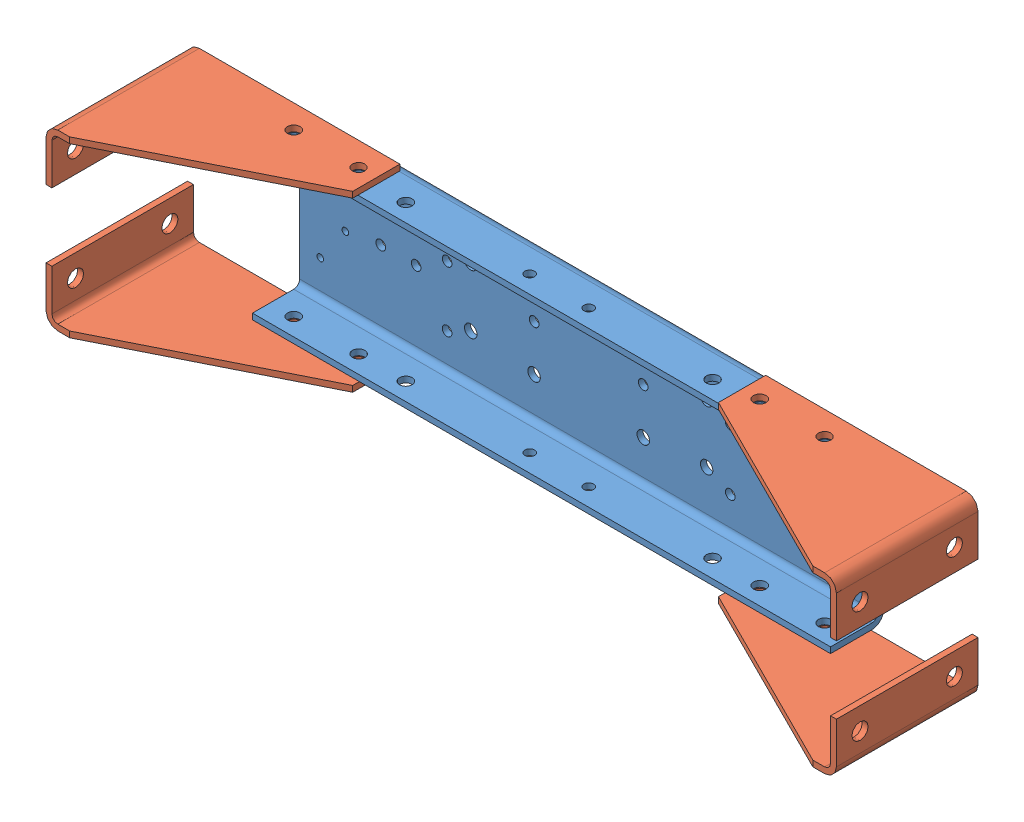
SolidWorks assembly SUB-1700-111, configuration Collapsed - No fasteners. Lengths in mm.
Overall size (850.9 187.32 165.1).
21 component instances, 4 part files, 56 mates.
Components (placement in the parent):
- 2686-CC2-1: 2686-CC2 [Default] at (0 0 -38.1) x (-1 0 0) z (0 0 -1)
- 2688-CC2-1: 2688-CC2 [2688-CC2-001] at (-425.45 -93.6625 0) x (1 0 0) z (0 0 -1)
- 2688-CC2-2: 2688-CC2 [2688-CC2-002] at (-425.45 93.6625 0)
- 2688-CC2-3: 2688-CC2 [2688-CC2-001] at (425.45 93.6625 0) x (-1 0 0) z (0 0 -1)
- 2688-CC2-4: 2688-CC2 [2688-CC2-002] at (425.45 -93.6625 0) x (-1 0 0) z (0 0 1)
- 08130XXXFH8Y-1: 08130XXXFH8Y [08130125FH8Y] at (-215.9 -93.6625 0) x (-0.388505 0 0.921447) z (0 -1 0) (suppressed, hidden)
- 08130XXXFH8Y-9: 08130XXXFH8Y [08130125FH8Y] at (215.9 93.6625 0) x (-0.948085 0 0.318017) z (0 1 0) (suppressed, hidden)
- 08130XXXFH8Y-7: 08130XXXFH8Y [08130125FH8Y] at (215.9 -93.6625 0) x (0.126811 0 0.991927) z (0 -1 0) (suppressed, hidden)
- 08130XXXFH8Y-11: 08130XXXFH8Y [08130125FH8Y] at (-215.9 93.6625 0) x (-0.668287 0 0.743903) z (0 1 0) (suppressed, hidden)
- 08130XXXFH8Y-2: 08130XXXFH8Y [08130125FH8Y] at (-285.75 -93.6625 0) x (0.84446 0 0.535618) z (0 -1 0) (suppressed, hidden)
- 08130XXXFH8Y-12: 08130XXXFH8Y [08130125FH8Y] at (-285.75 93.6625 0) x (-0.913136 0 -0.407655) z (0 1 0) (suppressed, hidden)
- 08130XXXFH8Y-10: 08130XXXFH8Y [08130125FH8Y] at (285.75 93.6625 0) x (-0.594714 0 0.803937) z (0 1 0) (suppressed, hidden)
- 08130XXXFH8Y-8: 08130XXXFH8Y [08130125FH8Y] at (285.75 -93.6625 0) x (0.463299 0 -0.886202) z (0 -1 0) (suppressed, hidden)
- XXXXFLN8Y-2: XXXXFLN8Y [0813FLN8Y] at (-285.75 -80.1688 0) x (0.884733 0 0.466098) z (0 1 0) (suppressed, hidden)
- XXXXFLN8Y-3: XXXXFLN8Y [0813FLN8Y] at (-215.9 80.1688 0) x (-0.573629 0 -0.819115) z (0 -1 0) (suppressed, hidden)
- XXXXFLN8Y-5: XXXXFLN8Y [0813FLN8Y] at (-285.75 80.1688 0) x (0.44022 0 0.89789) z (0 -1 0) (suppressed, hidden)
- XXXXFLN8Y-1: XXXXFLN8Y [0813FLN8Y] at (-215.9 -80.1688 0) x (0.278333 0 0.960485) z (0 1 0) (suppressed, hidden)
- XXXXFLN8Y-6: XXXXFLN8Y [0813FLN8Y] at (215.9 80.1688 0) x (0.382448 0 0.923977) z (0 -1 0) (suppressed, hidden)
- XXXXFLN8Y-7: XXXXFLN8Y [0813FLN8Y] at (215.9 -80.1688 0) x (0.126811 0 0.991927) z (0 1 0) (suppressed, hidden)
- XXXXFLN8Y-4: XXXXFLN8Y [0813FLN8Y] at (285.75 80.1688 0) x (0.994172 0 -0.107808) z (0 -1 0) (suppressed, hidden)
- XXXXFLN8Y-8: XXXXFLN8Y [0813FLN8Y] at (285.75 -80.1688 0) x (0.463299 0 -0.886202) z (0 1 0) (suppressed, hidden)
Mates (geometry in assembly coordinates):
- Coincident53: coincident anti-aligned: plane of 2686-CC2-1 through (0 0 -38.1) normal (-1 0 0)
- Coincident78: coincident aligned: unknown of 2686-CC2-1
- Concentric9: concentric anti-aligned: cylinder of ?; cylinder of ?
- Concentric10: concentric anti-aligned: cylinder of ?; cylinder of ?
- Coincident108: coincident anti-aligned: unknown of ?
- Coincident109: coincident anti-aligned: unknown of ?
- Concentric11: concentric anti-aligned: cylinder of ?; cylinder of ?
- Concentric12: concentric anti-aligned: cylinder of ?; cylinder of ?
- Coincident110: coincident anti-aligned: unknown of ?
- Coincident111: coincident anti-aligned: unknown of ?
- Concentric13: concentric anti-aligned: cylinder of ?; cylinder of ?
- Concentric14: concentric anti-aligned: cylinder of ?; cylinder of ?
- Coincident112: coincident anti-aligned: unknown of ?
- Coincident113: coincident anti-aligned: unknown of ?
- Concentric15: concentric anti-aligned: cylinder of ?; cylinder of ?
- Coincident114: coincident anti-aligned: unknown of ?
- Concentric16: concentric anti-aligned: cylinder of ?; cylinder of ?
- Coincident115: coincident anti-aligned: unknown of ?
- Distance11: distance = 425.45 mm aligned: plane of ?; plane of assembly
- Coincident130: coincident anti-aligned: plane of ?; plane of assembly
- Distance12: distance = 93.6625 mm anti-aligned: plane of ?; plane of assembly
- Distance13: distance = 93.6625 mm aligned: plane of ?; plane of assembly
- Distance14: distance = 425.45 mm aligned: plane of ?; plane of assembly
- Coincident135: coincident aligned: plane of ?; plane of assembly
- Coincident136: coincident aligned: plane of ?; plane of ?
- Coincident137: coincident aligned: plane of ?; plane of assembly
- Distance15: distance = 850.9 mm anti-aligned: plane of ?; plane of ?
- Coincident139: coincident aligned: plane of ?; plane of ?
- Coincident140: coincident anti-aligned: plane of ?; plane of ?
- Distance16: distance = 850.9 mm anti-aligned: plane of ?; plane of ?
- Coincident153: coincident aligned: plane of ?; plane of ?
- Coincident154: coincident aligned: plane of ?; plane of ?
- Coincident155: coincident aligned: plane of ?; plane of ?
- Coincident156: coincident anti-aligned: unknown of ?
- Coincident157: coincident aligned: plane of ?; plane of ?
- Coincident158: coincident aligned: plane of ?; plane of ?
- Coincident159: coincident aligned: plane of ?; plane of ?
- Coincident160: coincident aligned: plane of ?; plane of ?
- Coincident161: coincident aligned: plane of ?; plane of ?
- Coincident162: coincident aligned: plane of ?; plane of ?
- Coincident163: coincident anti-aligned: unknown of ?
- Coincident189: coincident anti-aligned: plane of ?; plane of ?
- Distance24: distance = 38.1 mm anti-aligned: unknown of 2686-CC2-1
- Concentric251: concentric aligned: unknown of 2686-CC2-1
- Concentric281: concentric aligned: unknown of 2686-CC2-1
- Concentric301: concentric aligned: unknown of 2686-CC2-1
- Concentric311: concentric aligned: unknown of 2686-CC2-1
- Coincident1971: coincident anti-aligned: plane of ?; plane of ?
- Concentric312: concentric anti-aligned: cylinder of ?; cylinder of ?
- Coincident1972: coincident anti-aligned: plane of ?; plane of ?
- Concentric313: concentric anti-aligned: cylinder of ?; cylinder of ?
- Coincident1973: coincident anti-aligned: plane of ?; plane of ?
- Concentric314: concentric anti-aligned: cylinder of ?; cylinder of ?
- Concentric315: concentric anti-aligned: cylinder of ?; cylinder of ?
- Coincident1974: coincident anti-aligned: plane of ?; plane of ?
- Coincident1975: coincident anti-aligned: 
